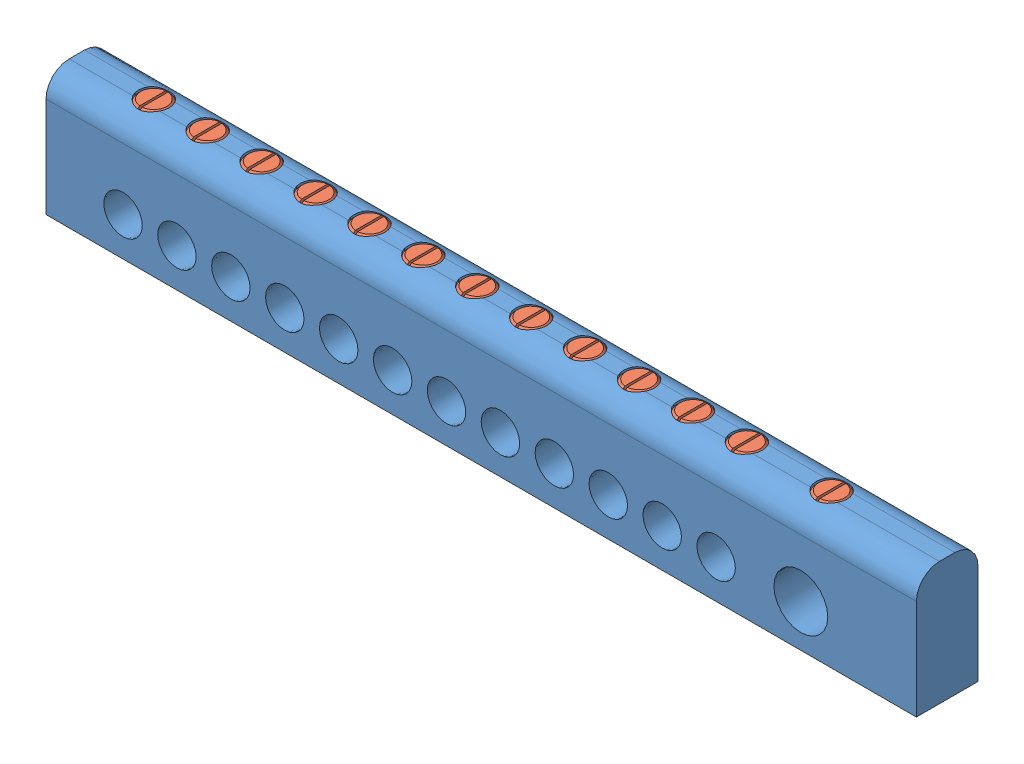
SolidWorks assembly Assemblage1, configuration Défaut. Lengths in mm.
Overall size (113 16 8).
14 component instances, 2 part files, 27 mates.
Components (placement in the parent):
- bornier_rampe-1: bornier_rampe [Défaut] at origin size (113 16 8)
- Vis sans tête fendue à bout bombé, M 3-3-1: Vis sans tête fendue à bout bombé, M 3-3 [Défaut] at (45 0 4) size (4 10 4)
- Vis sans tête fendue à bout bombé, M 3-3-2: Vis sans tête fendue à bout bombé, M 3-3 [Défaut] at (59 0 4) size (4 10 4)
- Vis sans tête fendue à bout bombé, M 3-3-3: Vis sans tête fendue à bout bombé, M 3-3 [Défaut] at (87 0 4) size (4 10 4)
- Vis sans tête fendue à bout bombé, M 3-3-4: Vis sans tête fendue à bout bombé, M 3-3 [Défaut] at (73 0 4) size (4 10 4)
- Vis sans tête fendue à bout bombé, M 3-3-5: Vis sans tête fendue à bout bombé, M 3-3 [Défaut] at (80 0 4) size (4 10 4)
- Vis sans tête fendue à bout bombé, M 3-3-6: Vis sans tête fendue à bout bombé, M 3-3 [Défaut] at (66 0 4) size (4 10 4)
- Vis sans tête fendue à bout bombé, M 3-3-7: Vis sans tête fendue à bout bombé, M 3-3 [Défaut] at (52 0 4) size (4 10 4)
- Vis sans tête fendue à bout bombé, M 3-3-8: Vis sans tête fendue à bout bombé, M 3-3 [Défaut] at (38 0 4) size (4 10 4)
- Vis sans tête fendue à bout bombé, M 3-3-9: Vis sans tête fendue à bout bombé, M 3-3 [Défaut] at (31 0 4) size (4 10 4)
- Vis sans tête fendue à bout bombé, M 3-3-10: Vis sans tête fendue à bout bombé, M 3-3 [Défaut] at (24 0 4) size (4 10 4)
- Vis sans tête fendue à bout bombé, M 3-3-11: Vis sans tête fendue à bout bombé, M 3-3 [Défaut] at (17 0 4) size (4 10 4)
- Vis sans tête fendue à bout bombé, M 3-3-12: Vis sans tête fendue à bout bombé, M 3-3 [Défaut] at (10 0 4) size (4 10 4)
- Vis sans tête fendue à bout bombé, M 3-3-13: Vis sans tête fendue à bout bombé, M 3-3 [Défaut] at (98 0 4) size (4 10 4)
Mates (geometry in assembly coordinates):
- Coaxiale1: concentric anti-aligned: cylinder of bornier_rampe-1 through (10 -10 4) axis (0 1 0) radius 2; cylinder of Vis sans tête fendue à bout bombé, M 3-3-12 through (10 0 4) axis (0 -1 0) radius 2
- Coaxiale2: concentric anti-aligned: cylinder of bornier_rampe-1 through (17 -10 4) axis (0 1 0) radius 2; cylinder of Vis sans tête fendue à bout bombé, M 3-3-11 through (17 0 4) axis (0 -1 0) radius 2
- Coaxiale3: concentric anti-aligned: cylinder of bornier_rampe-1 through (24 -10 4) axis (0 1 0) radius 2; cylinder of Vis sans tête fendue à bout bombé, M 3-3-10 through (24 0 4) axis (0 -1 0) radius 2
- Coaxiale4: concentric anti-aligned: cylinder of bornier_rampe-1 through (31 -10 4) axis (0 1 0) radius 2; cylinder of Vis sans tête fendue à bout bombé, M 3-3-9 through (31 0 4) axis (0 -1 0) radius 2
- Coaxiale5: concentric anti-aligned: cylinder of bornier_rampe-1 through (38 -10 4) axis (0 1 0) radius 2; circle of Vis sans tête fendue à bout bombé, M 3-3-8
- Coaxiale6: concentric anti-aligned: cylinder of bornier_rampe-1 through (45 -10 4) axis (0 1 0) radius 2; cylinder of Vis sans tête fendue à bout bombé, M 3-3-1 through (45 0 4) axis (0 -1 0) radius 2
- Coaxiale7: concentric anti-aligned: cylinder of bornier_rampe-1 through (98 -10 4) axis (0 1 0) radius 2; cylinder of Vis sans tête fendue à bout bombé, M 3-3-13 through (98 0 4) axis (0 -1 0) radius 2
- Coaxiale8: concentric anti-aligned: cylinder of bornier_rampe-1 through (87 -10 4) axis (0 1 0) radius 2; cylinder of Vis sans tête fendue à bout bombé, M 3-3-3 through (87 0 4) axis (0 -1 0) radius 2
- Coaxiale9: concentric anti-aligned: cylinder of bornier_rampe-1 through (80 -10 4) axis (0 1 0) radius 2; cylinder of Vis sans tête fendue à bout bombé, M 3-3-5 through (80 0 4) axis (0 -1 0) radius 2
- Coaxiale10: concentric anti-aligned: cylinder of bornier_rampe-1 through (73 -10 4) axis (0 1 0) radius 2; cylinder of Vis sans tête fendue à bout bombé, M 3-3-4 through (73 0 4) axis (0 -1 0) radius 2
- Coaxiale11: concentric anti-aligned: cylinder of bornier_rampe-1 through (66 -10 4) axis (0 1 0) radius 2; cylinder of Vis sans tête fendue à bout bombé, M 3-3-6 through (66 0 4) axis (0 -1 0) radius 2
- Coaxiale12: concentric anti-aligned: cylinder of bornier_rampe-1 through (59 -10 4) axis (0 1 0) radius 2; cylinder of Vis sans tête fendue à bout bombé, M 3-3-2 through (59 0 4) axis (0 -1 0) radius 2
- Coaxiale13: concentric anti-aligned: cylinder of bornier_rampe-1 through (52 -10 4) axis (0 1 0) radius 2; cylinder of Vis sans tête fendue à bout bombé, M 3-3-7 through (52 0 4) axis (0 -1 0) radius 2
- Coïncidente14: coincident aligned: plane of Vis sans tête fendue à bout bombé, M 3-3-12 through (10 0 4) normal (0 1 0); plane of bornier_rampe-1 through (0 0 8) normal (0 1 0)
- Coïncidente15: coincident aligned: plane of Vis sans tête fendue à bout bombé, M 3-3-11 through (17 0 4) normal (0 1 0); plane of bornier_rampe-1 through (0 0 8) normal (0 1 0)
- Coïncidente16: coincident aligned: plane of Vis sans tête fendue à bout bombé, M 3-3-10 through (24 0 4) normal (0 1 0); plane of bornier_rampe-1 through (0 0 8) normal (0 1 0)
- Coïncidente17: coincident aligned: plane of Vis sans tête fendue à bout bombé, M 3-3-9 through (31 0 4) normal (0 1 0); plane of bornier_rampe-1 through (0 0 8) normal (0 1 0)
- Coïncidente18: coincident aligned: plane of Vis sans tête fendue à bout bombé, M 3-3-8 through (38 0 4) normal (0 1 0); plane of bornier_rampe-1 through (0 0 8) normal (0 1 0)
- Coïncidente19: coincident aligned: plane of Vis sans tête fendue à bout bombé, M 3-3-8 through (38 0 4) normal (0 1 0); plane of bornier_rampe-1 through (0 0 8) normal (0 1 0)
- Coïncidente20: coincident aligned: plane of Vis sans tête fendue à bout bombé, M 3-3-1 through (45 0 4) normal (0 1 0); plane of bornier_rampe-1 through (0 0 8) normal (0 1 0)
- Coïncidente21: coincident aligned: plane of Vis sans tête fendue à bout bombé, M 3-3-7 through (52 0 4) normal (0 1 0); plane of bornier_rampe-1 through (0 0 8) normal (0 1 0)
- Coïncidente22: coincident aligned: plane of Vis sans tête fendue à bout bombé, M 3-3-2 through (59 0 4) normal (0 1 0); plane of bornier_rampe-1 through (0 0 8) normal (0 1 0)
- Coïncidente23: coincident aligned: plane of Vis sans tête fendue à bout bombé, M 3-3-6 through (66 0 4) normal (0 1 0); plane of bornier_rampe-1 through (0 0 8) normal (0 1 0)
- Coïncidente24: coincident aligned: plane of Vis sans tête fendue à bout bombé, M 3-3-4 through (73 0 4) normal (0 1 0); plane of bornier_rampe-1 through (0 0 8) normal (0 1 0)
- Coïncidente25: coincident aligned: plane of Vis sans tête fendue à bout bombé, M 3-3-5 through (80 0 4) normal (0 1 0); plane of bornier_rampe-1 through (0 0 8) normal (0 1 0)
- Coïncidente26: coincident aligned: plane of Vis sans tête fendue à bout bombé, M 3-3-3 through (87 0 4) normal (0 1 0); plane of bornier_rampe-1 through (0 0 8) normal (0 1 0)
- Coïncidente27: coincident aligned: plane of Vis sans tête fendue à bout bombé, M 3-3-13 through (98 0 4) normal (0 1 0); plane of bornier_rampe-1 through (0 0 8) normal (0 1 0)
